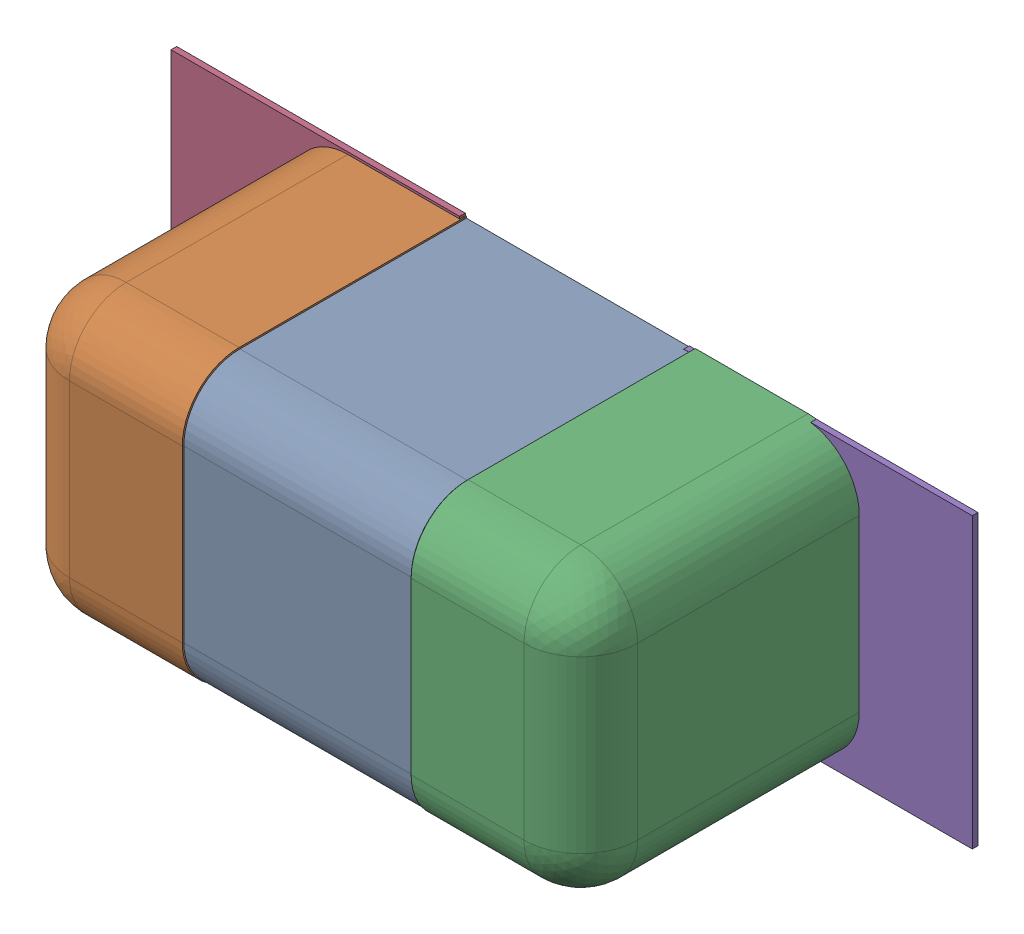
SolidWorks assembly C78, configuration Défaut. Lengths in mm.
Overall size (1.41 0.51 0.5).
8 component instances, 4 part files, 0 mates.
Components (placement in the parent):
- 6324936752-1: 6324936752 [Défaut] at (9.8044 -34.4424 0) x (1 0 0) z (0 -1 0) size (1 0.5 0.5)
  - Open CASCADE STEP translator 7.5 2.114.1.1-1: Open CASCADE STEP translator 7.5 2.114.1.1 [Défaut] at origin size (0.4 0.5 0.5)
  - Open CASCADE STEP translator 7.5 2.114.1.2-1: Open CASCADE STEP translator 7.5 2.114.1.2 [Défaut] at origin size (0.3 0.5 0.5)
  - Open CASCADE STEP translator 7.5 2.114.1.3-1: Open CASCADE STEP translator 7.5 2.114.1.3 [Défaut] at origin size (0.3 0.5 0.5)
- 6504207776-1: 6504207776 [Défaut] at (9.3471 -34.4424 0) size (0.51 0.51 0.01)
  - Extruded-1: Extruded [Défaut] at origin size (0.51 0.51 0.01)
- 6504207776-2: 6504207776 [Défaut] at (10.2494 -34.4476 0) size (0.51 0.51 0.01)
  - Extruded-1: Extruded [Défaut] at origin size (0.51 0.51 0.01)
